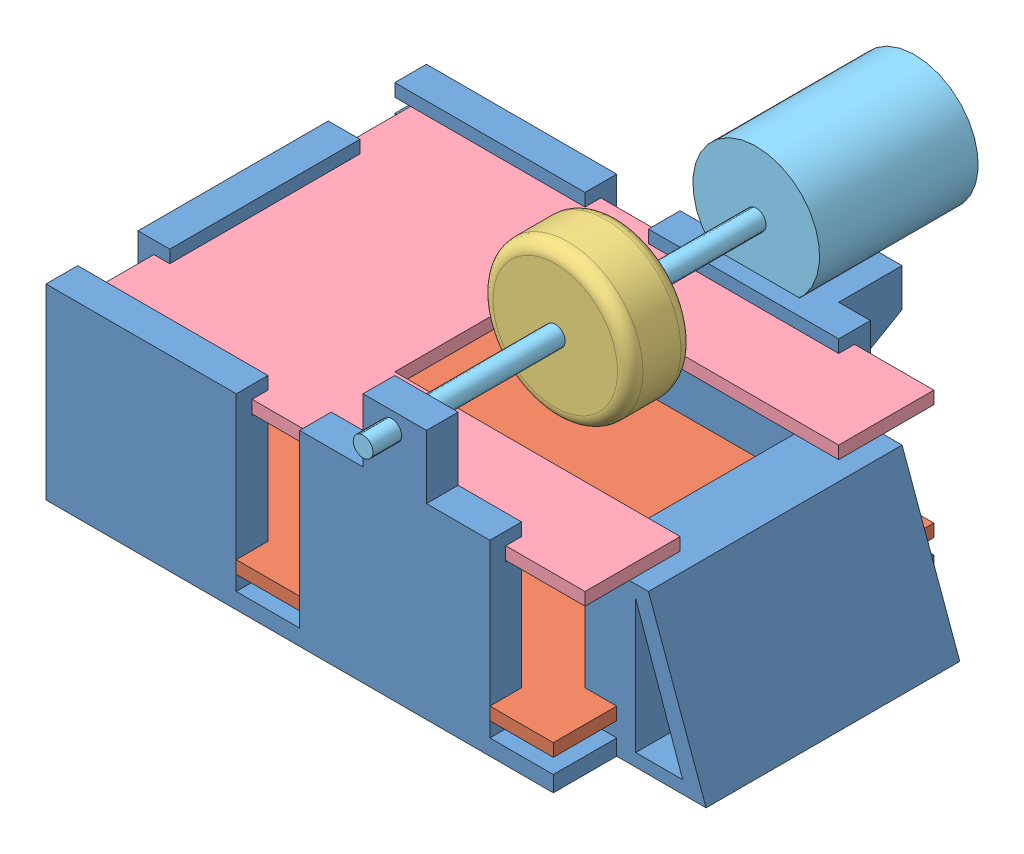
SolidWorks assembly Card shooter assembly, configuration Default. Lengths in mm.
Overall size (119.51 67.53 110.49).
6 component instances, 6 part files, 10 mates.
Components (placement in the parent):
- card shooter-1: card shooter [Default] at (27.8855 16.6943 85.3146) size (119.51 50.16 88.9)
- Card shooter plate-1: Card shooter plate [Default] at (0 405.4973 0) size (101.6 2.54 76.2)
- Shooter wheel-3: Shooter wheel [Default] at (50.802 136.4048 297.4447) x (-0.553979 -0.832531 0) z (0 0 1) size (30 30 12.7)
- Model locker door-1: Model locker door [Default] at (53.6759 142.0307 -78.8467) x (0.34202 -0.939693 0) z (0 0 -1) size (609.6 2.54 304.8) (hidden)
- new card shooter plate-1: new card shooter plate [Default] at (81.8605 49.0793 120.2396) x (0 0 -1) z (1 0 0) size (69.85 2.54 101.6)
- new card shooter motor-1: new card shooter motor [Default] at (46.3057 63.4303 18.6396) x (0.02551 -0.999675 0) z (0 0 1) size (25.4 25.4 110.49)
Mates (geometry in assembly coordinates):
- Distance8: distance = 10.541 mm: line of assembly; line of card shooter-1 through (40.5855 56.6993 117.3186) axis (0 0 1)
- Coincident38: coincident anti-aligned: plane of card shooter-1 through (-19.7395 51.6193 109.0412) normal (1 0 0); plane of new card shooter plate-1 through (-19.7395 51.6193 120.2396) normal (-1 0 0)
- Coincident39: coincident anti-aligned: plane of card shooter-1 through (-25.7085 51.6193 120.2396) normal (0 0 -1); plane of new card shooter plate-1 through (81.8605 51.6193 120.2396) normal (0 0 1)
- Coincident40: coincident anti-aligned: plane of card shooter-1 through (-25.7085 51.6193 117.0646) normal (0 -1 0); plane of new card shooter plate-1 through (81.8605 51.6193 120.2396) normal (0 1 0)
- Concentric1: concentric aligned: circle of card shooter-1; circle of Shooter wheel-3
- Distance9: distance = 26.425 mm anti-aligned: plane of card shooter-1 through (27.8855 54.1593 117.0646) normal (0 0 -1); plane of Shooter wheel-3 through (46.3057 63.4303 90.6396) normal (0 0 1)
- Concentric2: concentric anti-aligned: circle of card shooter-1; circle of new card shooter motor-1
- Distance10: distance = 3.175 mm aligned: plane of new card shooter motor-1 through (46.3057 63.4303 50.3896) normal (0 0 1); plane of card shooter-1 through (65.9855 54.1593 53.5646) normal (0 0 1)
- Coincident43: coincident aligned: plane of card shooter-1 through (-22.9145 19.8693 123.4146) normal (-1 0 0); plane of Card shooter plate-1 through (-22.9145 25.396 0) normal (-1 0 0)
- Coincident44: coincident aligned: plane of card shooter-1 through (-22.9145 19.8693 123.4146) normal (0 0 1); plane of Card shooter plate-1 through (0 25.396 123.4146) normal (0 0 1)
